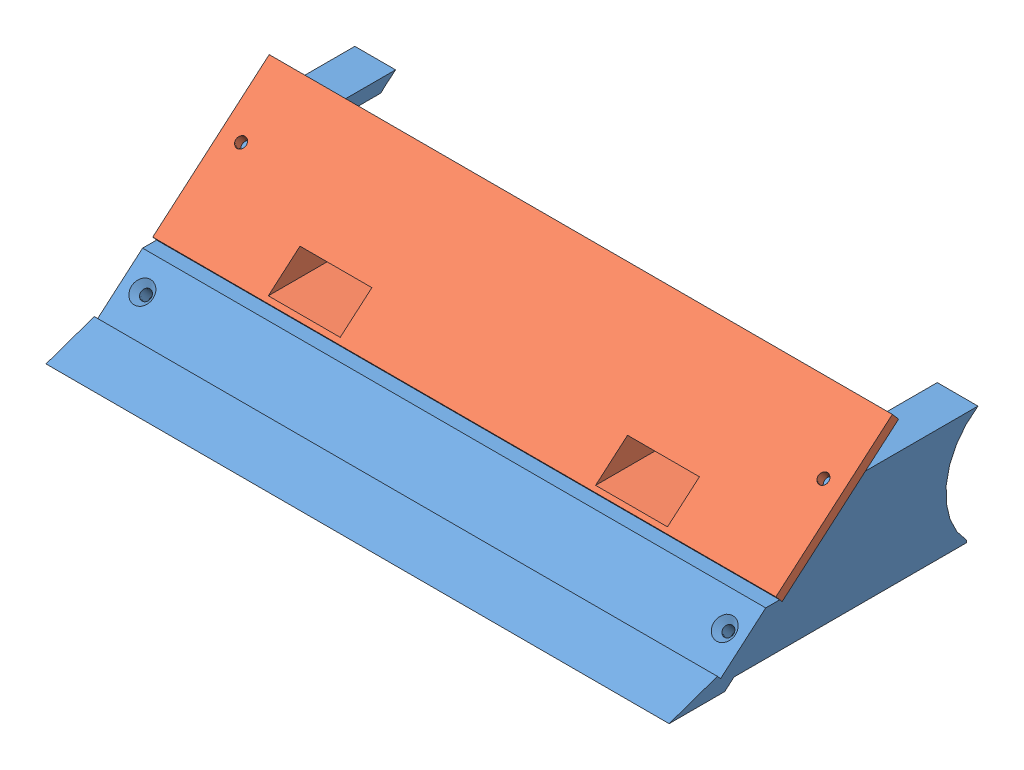
SolidWorks assembly FrenteEnsambladoV2, configuration Predeterminado. Lengths in mm.
Overall size (195 48.91 96.65).
2 component instances, 2 part files, 5 mates.
Components (placement in the parent):
- FrenteEnsamblado-1: FrenteEnsamblado [Predeterminado] at (-127.6995 -10.4905 150.2381) size (195 37.75 96.65)
- 2022-Sensores_Sharp_RyO-1: 2022-Sensores_Sharp_RyO [Predeterminado] at (-30.1995 30.3902 175.325) x (-1 0 0) z (0 0.759271 0.650774) size (195 48 13.45)
Mates (geometry in assembly coordinates):
- Coincidente1: coincident: plane of FrenteEnsamblado-1 through (-127.6995 -10.4905 150.2381) normal (-1 0 0); plane of 2022-Sensores_Sharp_SAMI-1 through (-127.6995 36.2292 173.1224) normal (-1 0 0)
- Coincidente2: coincident: plane of FrenteEnsamblado-1 through (-127.6995 -10.4905 223.0213) normal (0 0.759271 0.650774); plane of 2022-Sensores_Sharp_SAMI-1 through (-30.1995 33.9514 171.1701) normal (0 -0.759271 -0.650774)
- Coincidente3: coincident: line of FrenteEnsamblado-1 through (67.3005 3.2788 213.1029) axis (-1 0 0); plane of 2022-Sensores_Sharp_SAMI-1 through (-127.6995 2.5195 212.4521) normal (0 -0.650774 0.759271)
- Coincidente4: coincident anti-aligned: plane of FrenteEnsamblado-1 through (41.8005 -10.4905 223.0213) normal (0 0.759271 0.650774); plane of 2022-Sensores_Sharp_RyO-1 through (-30.1995 30.3902 175.325) normal (0 -0.759271 -0.650774)
- Coincidente5: coincident aligned: plane of FrenteEnsamblado-1 through (-127.6995 -10.4905 150.2381) normal (-1 0 0); plane of 2022-Sensores_Sharp_RyO-1 through (-127.6995 32.668 177.2773) normal (-1 0 0)
